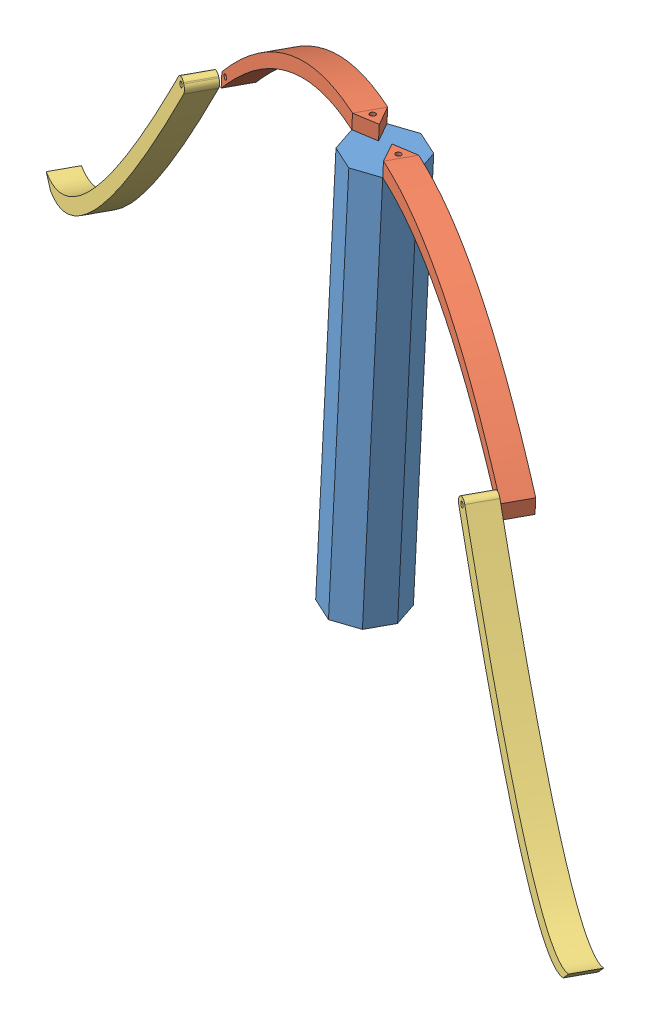
SolidWorks assembly jellyfish, configuration Default. Lengths in mm.
Overall size (387.85 160.39 188.42).
5 component instances, 3 part files, 11 mates.
Components (placement in the parent):
- stem-1: stem [Default] at (-255.7804 154.0602 150.2843) x (0.279375 -0.046615 -0.95905) z (0.960163 0.007174 0.27935) size (26.71 152.4 26.71)
- finA-2: finA [Default] at (-269.5133 154.1164 149.6824) x (0.422527 -0.044976 -0.905234) z (0.906329 0.014199 0.422333) size (10.52 56.39 109.11)
- finA-3: finA [Default] at (-242.0473 154.0039 150.886) x (-0.422527 0.044976 0.905234) z (-0.906329 -0.014199 -0.422333) size (10.52 56.39 109.11)
- finB-1: finB [Default] at (-160.4311 110.7595 202.7518) x (-0.422527 0.044976 0.905234) z (-0.9063 -0.031471 -0.421462) size (10.52 108.67 99.06)
- finB-2: finB [Default] at (-361.7238 108.1981 123.5525) x (0.422527 -0.044976 -0.905234) z (0.905234 -0.028621 0.423949) size (10.52 108.67 99.06)
Mates (geometry in assembly coordinates):
- Parallel11: parallel anti-aligned: plane of stem-1 through (-255.7804 154.0602 150.2843) normal (0.006141 0.998887 -0.046763); plane of finA-3 through (-242.0473 154.0039 150.886) normal (-0.006141 -0.998887 0.046763)
- Coincident15: coincident: point of stem-1; point of finA-3
- Coincident16: coincident: point of stem-1; point of finA-3
- Parallel12: parallel anti-aligned: plane of stem-1 through (-255.7804 154.0602 150.2843) normal (0.006141 0.998887 -0.046763); plane of finA-2 through (-269.5133 154.1164 149.6824) normal (-0.006141 -0.998887 0.046763)
- Coincident17: coincident: point of stem-1; point of finA-2
- Coincident18: coincident: point of stem-1; point of finA-2
- Parallel13: parallel anti-aligned: plane of finA-3 through (-196.0837 142.0393 172.9344) normal (0.422527 -0.044976 -0.905234); plane of finB-1 through (-111.2318 32.3063 241.2361) normal (-0.422527 0.044976 0.905234)
- Concentric1: concentric aligned: cylinder of finA-3 through (-158.3611 110.8421 206.7461) axis (0.422527 -0.044976 -0.905234) radius 0.9705; cylinder of finB-1 through (-161.6466 111.1918 213.7851) axis (0.422527 -0.044976 -0.905234) radius 1.016
- Coincident19: coincident anti-aligned: plane of finA-3 through (-200.529 142.5125 182.4581) normal (-0.422527 0.044976 0.905234); plane of finB-1 through (-106.7865 31.8331 231.7124) normal (0.422527 -0.044976 -0.905234)
- Parallel14: parallel anti-aligned: plane of finA-2 through (-315.6328 140.7092 128.8217) normal (-0.422527 0.044976 0.905234); plane of finB-2 through (-413.7277 28.6253 91.6106) normal (0.422527 -0.044976 -0.905234)
- Concentric2: concentric aligned: cylinder of finA-2 through (-353.7548 106.9548 98.0507) axis (-0.422527 0.044976 0.905234) radius 0.9705; cylinder of finB-2 through (-360.51 107.6739 112.5231) axis (-0.422527 0.044976 0.905234) radius 1.016
